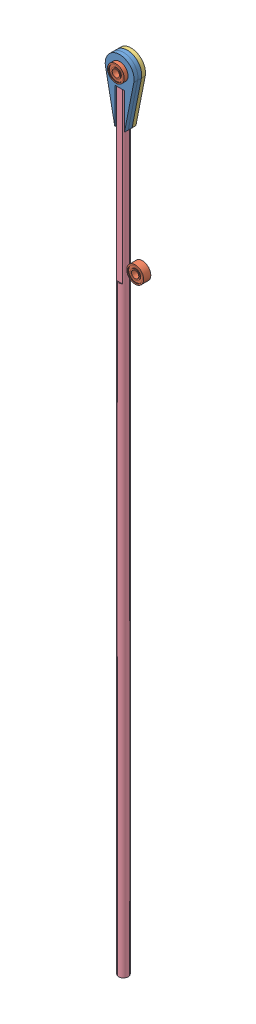
SolidWorks assembly root assem, configuration Default. Lengths in mm.
Overall size (18.96 332 6.35).
7 component instances, 4 part files, 19 mates.
Components (placement in the parent):
- middles-1: middles [Default] at (4.4373 9.5952 25.8576) size (12 27 1.59)
- 3x7mm-2: 3x7mm [Default] at (4.4373 9.5952 22.6801) size (7 7 3)
- ends-2: ends [Default] at (4.4373 9.5952 22.6801) x (1 -0.000058 0) z (0 0 1) size (12 27 1.59)
- middles-2: middles [Default] at (4.4373 9.5952 24.2676) x (1 -0.000062 0) z (0 0 1) size (12 27 1.59)
- inner spar-1: inner spar [Default] at (4.4369 3.5952 25.8601) x (0 0 -1) z (0 -1 0) size (4 4 320)
- 3x7mm-3: 3x7mm [Default] at (12.4821 -58.8272 26.0351) x (-0.782033 0.623237 0) z (0 0 1) size (7 7 3)
- 3x7mm-4: 3x7mm [Default] at (4.4358 9.5954 26.0351) size (7 7 3)
Mates (geometry in assembly coordinates):
- Concentric1: concentric: cylinder of ? through (4.4373 9.5952 29.0351) axis (0 0 -1) radius 3.5; cylinder of ? through (4.4373 9.5952 29.0351) axis (0 0 -1) radius 3.5
- Coincident1: coincident: plane of ? through (4.4373 9.5952 29.0351) normal (0 0 1); plane of ? through (4.4373 9.5952 29.0351) normal (0 0 1)
- Concentric2: concentric: cylinder of middles-1 through (4.4373 9.5952 27.4476) axis (0 0 -1) radius 3.5; cylinder of ? through (4.4373 9.5952 29.0351) axis (0 0 -1) radius 3.5
- Coincident2: coincident: plane of middles-1 through (4.4373 9.5952 27.4476) normal (0 0 1); plane of ? through (4.4358 9.5954 27.4476) normal (0 0 -1)
- Concentric3: concentric aligned: cylinder of 3x7mm-2 through (4.4373 9.5952 25.6801) axis (0 0 -1) radius 3.5; cylinder of ends-2 through (4.4373 9.5952 24.2676) axis (0 0 -1) radius 3.5
- Coincident3: coincident aligned: plane of 3x7mm-2 through (4.4373 9.5952 22.6801) normal (0 0 -1); plane of ends-2 through (4.4373 9.5952 22.6801) normal (0 0 -1)
- Concentric4: concentric aligned: cylinder of 3x7mm-2 through (4.4373 9.5952 25.6801) axis (0 0 -1) radius 3.5; cylinder of middles-2 through (4.4373 9.5952 25.8576) axis (0 0 -1) radius 3.5
- Coincident5: coincident anti-aligned: plane of ends-2 through (4.4373 9.5952 24.2676) normal (0 0 1); plane of middles-2 through (4.4373 9.5952 24.2676) normal (0 0 -1)
- Coincident6: coincident anti-aligned: plane of middles-1 through (4.4373 9.5952 25.8576) normal (0 0 -1); plane of middles-2 through (4.4373 9.5952 25.8576) normal (0 0 1)
- Concentric5: concentric aligned: cylinder of middles-1 through (4.4373 9.5952 27.4476) axis (0 0 -1) radius 6; cylinder of ends-2 through (4.4373 9.5952 24.2676) axis (0 0 -1) radius 6
- Coincident7: coincident anti-aligned: plane of middles-1 through (2.4373 3.5952 27.4476) normal (0 -1 0); plane of inner spar-1 through (4.4369 3.5952 25.8601) normal (0 1 0)
- Coincident8: coincident: plane of ? through (4.4358 9.5954 27.4476) normal (0 0 -1); plane of inner spar-1 through (5.6534 -66.4048 27.4476) normal (0 0 1)
- Coincident9: coincident: line of middles-2 through (2.4369 -11.4045 25.8576) axis (0 1 0); cylinder of inner spar-1 through (4.4369 -316.4048 25.8601) axis (0 1 0) radius 2
- Concentric6: concentric: cylinder of ? through (12.4821 -58.8272 29.0351) axis (0 0 -1) radius 3.5; cylinder of 3x7mm-3 through (12.4821 -58.8272 29.0351) axis (0 0 -1) radius 3.5
- Coincident10: coincident: plane of middles-1 through (2.4383 -11.4046 27.4476) normal (-0.981336 -0.192299 0); plane of ? through (2.4383 -11.4046 29.0351) normal (-0.981336 -0.192299 0)
- Coincident11: coincident aligned: plane of ends-2 through (2.437 -11.4045 24.2676) normal (-0.981348 -0.192238 0); plane of middles-2 through (2.4369 -11.4045 25.8576) normal (-0.981348 -0.192238 0)
- Coincident12: coincident: plane of ? through (4.4358 9.5954 29.0351) normal (0 0 1); plane of 3x7mm-3 through (12.4821 -58.8272 29.0351) normal (0 0 1)
- Concentric7: concentric: cylinder of ? through (4.4358 9.5954 29.0351) axis (0 0 -1) radius 3.5; cylinder of 3x7mm-4 through (4.4358 9.5954 29.0351) axis (0 0 -1) radius 3.5
- Coincident13: coincident: plane of ? through (4.4358 9.5954 29.0351) normal (0 0 1); plane of 3x7mm-4 through (4.4358 9.5954 29.0351) normal (0 0 1)
